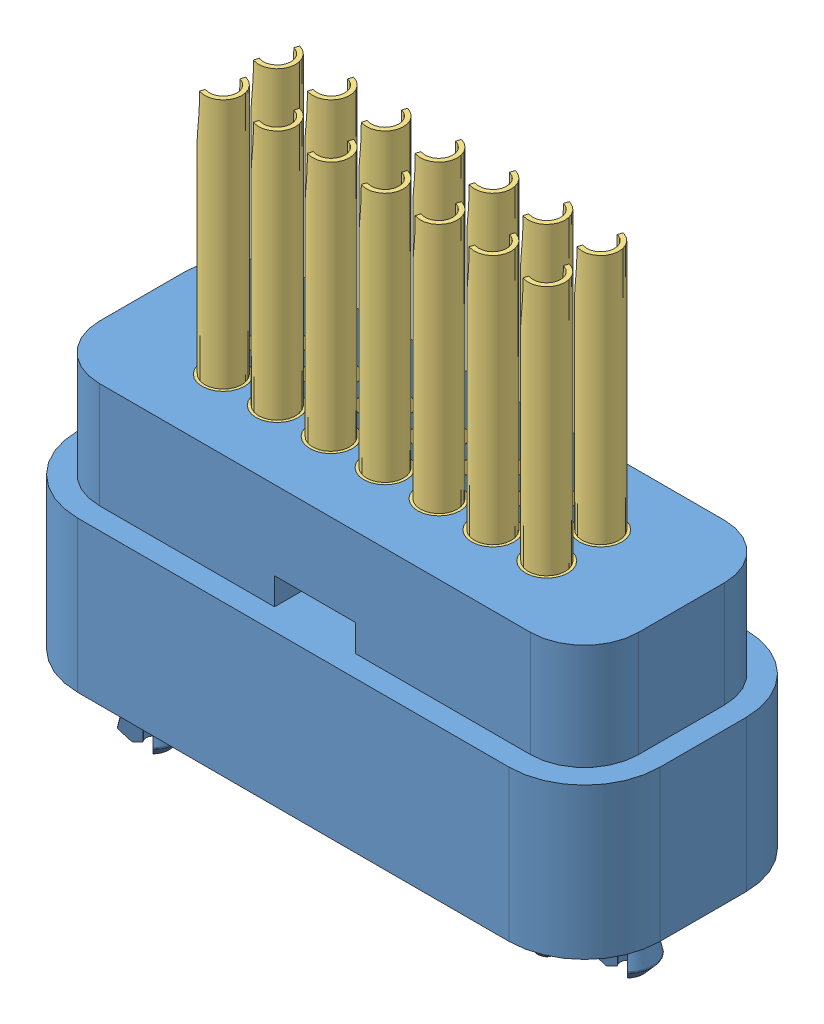
SolidWorks assembly Assem3, configuration Default. Lengths in mm.
Overall size (13.72 13.98 5.59).
43 component instances, 3 part files, 2 mates.
Components (placement in the parent):
- Part4-1: Part4 [Default] at origin size (13.72 7.95 5.59)
- 90049 Clip-in-line-1: 90049 Clip-in-line [Default] at (0 -1.95 0) x (0 1 0) z (-0.298389 0 0.954444) size (13.98 1.06 1.06)
  - 50254-1: 50254 [Default] at origin size (7.79 0.91 0.91)
  - 65007-1: 65007 [Default] at (5.45 0 0) size (8.53 1.06 1.06)
- 90049 Clip-in-line-2: 90049 Clip-in-line [Default] at (0 -1.95 -1.27) x (0 1 0) z (-0.298389 0 0.954444) size (13.98 1.06 1.06)
  - 50254-1: 50254 [Default] at origin size (7.79 0.91 0.91)
  - 65007-1: 65007 [Default] at (5.45 0 0) size (8.53 1.06 1.06)
- 90049 Clip-in-line-3: 90049 Clip-in-line [Default] at (1.27 -1.95 0) x (0 1 0) z (-0.298389 0 0.954444) size (13.98 1.06 1.06)
  - 50254-1: 50254 [Default] at origin size (7.79 0.91 0.91)
  - 65007-1: 65007 [Default] at (5.45 0 0) size (8.53 1.06 1.06)
- 90049 Clip-in-line-4: 90049 Clip-in-line [Default] at (1.27 -1.95 -1.27) x (0 1 0) z (-0.298389 0 0.954444) size (13.98 1.06 1.06)
  - 50254-1: 50254 [Default] at origin size (7.79 0.91 0.91)
  - 65007-1: 65007 [Default] at (5.45 0 0) size (8.53 1.06 1.06)
- 90049 Clip-in-line-5: 90049 Clip-in-line [Default] at (2.54 -1.95 0) x (0 1 0) z (-0.298389 0 0.954444) size (13.98 1.06 1.06)
  - 50254-1: 50254 [Default] at origin size (7.79 0.91 0.91)
  - 65007-1: 65007 [Default] at (5.45 0 0) size (8.53 1.06 1.06)
- 90049 Clip-in-line-6: 90049 Clip-in-line [Default] at (2.54 -1.95 -1.27) x (0 1 0) z (-0.298389 0 0.954444) size (13.98 1.06 1.06)
  - 50254-1: 50254 [Default] at origin size (7.79 0.91 0.91)
  - 65007-1: 65007 [Default] at (5.45 0 0) size (8.53 1.06 1.06)
- 90049 Clip-in-line-7: 90049 Clip-in-line [Default] at (3.81 -1.95 0) x (0 1 0) z (-0.298389 0 0.954444) size (13.98 1.06 1.06)
  - 50254-1: 50254 [Default] at origin size (7.79 0.91 0.91)
  - 65007-1: 65007 [Default] at (5.45 0 0) size (8.53 1.06 1.06)
- 90049 Clip-in-line-8: 90049 Clip-in-line [Default] at (3.81 -1.95 -1.27) x (0 1 0) z (-0.298389 0 0.954444) size (13.98 1.06 1.06)
  - 50254-1: 50254 [Default] at origin size (7.79 0.91 0.91)
  - 65007-1: 65007 [Default] at (5.45 0 0) size (8.53 1.06 1.06)
- 90049 Clip-in-line-9: 90049 Clip-in-line [Default] at (5.08 -1.95 0) x (0 1 0) z (-0.298389 0 0.954444) size (13.98 1.06 1.06)
  - 50254-1: 50254 [Default] at origin size (7.79 0.91 0.91)
  - 65007-1: 65007 [Default] at (5.45 0 0) size (8.53 1.06 1.06)
- 90049 Clip-in-line-10: 90049 Clip-in-line [Default] at (5.08 -1.95 -1.27) x (0 1 0) z (-0.298389 0 0.954444) size (13.98 1.06 1.06)
  - 50254-1: 50254 [Default] at origin size (7.79 0.91 0.91)
  - 65007-1: 65007 [Default] at (5.45 0 0) size (8.53 1.06 1.06)
- 90049 Clip-in-line-11: 90049 Clip-in-line [Default] at (6.35 -1.95 0) x (0 1 0) z (-0.298389 0 0.954444) size (13.98 1.06 1.06)
  - 50254-1: 50254 [Default] at origin size (7.79 0.91 0.91)
  - 65007-1: 65007 [Default] at (5.45 0 0) size (8.53 1.06 1.06)
- 90049 Clip-in-line-12: 90049 Clip-in-line [Default] at (6.35 -1.95 -1.27) x (0 1 0) z (-0.298389 0 0.954444) size (13.98 1.06 1.06)
  - 50254-1: 50254 [Default] at origin size (7.79 0.91 0.91)
  - 65007-1: 65007 [Default] at (5.45 0 0) size (8.53 1.06 1.06)
- 90049 Clip-in-line-13: 90049 Clip-in-line [Default] at (7.62 -1.95 0) x (0 1 0) z (-0.298389 0 0.954444) size (13.98 1.06 1.06)
  - 50254-1: 50254 [Default] at origin size (7.79 0.91 0.91)
  - 65007-1: 65007 [Default] at (5.45 0 0) size (8.53 1.06 1.06)
- 90049 Clip-in-line-14: 90049 Clip-in-line [Default] at (7.62 -1.95 -1.27) x (0 1 0) z (-0.298389 0 0.954444) size (13.98 1.06 1.06)
  - 50254-1: 50254 [Default] at origin size (7.79 0.91 0.91)
  - 65007-1: 65007 [Default] at (5.45 0 0) size (8.53 1.06 1.06)
Mates (geometry in assembly coordinates):
- Coincident1: coincident anti-aligned: plane of Part4-1 through (0 0 0) normal (0 -1 0); circle of 90049 Clip-in-line-1/50254-1
- Concentric1: concentric: circle of Part4-1; circle of 90049 Clip-in-line-1/65007-1
